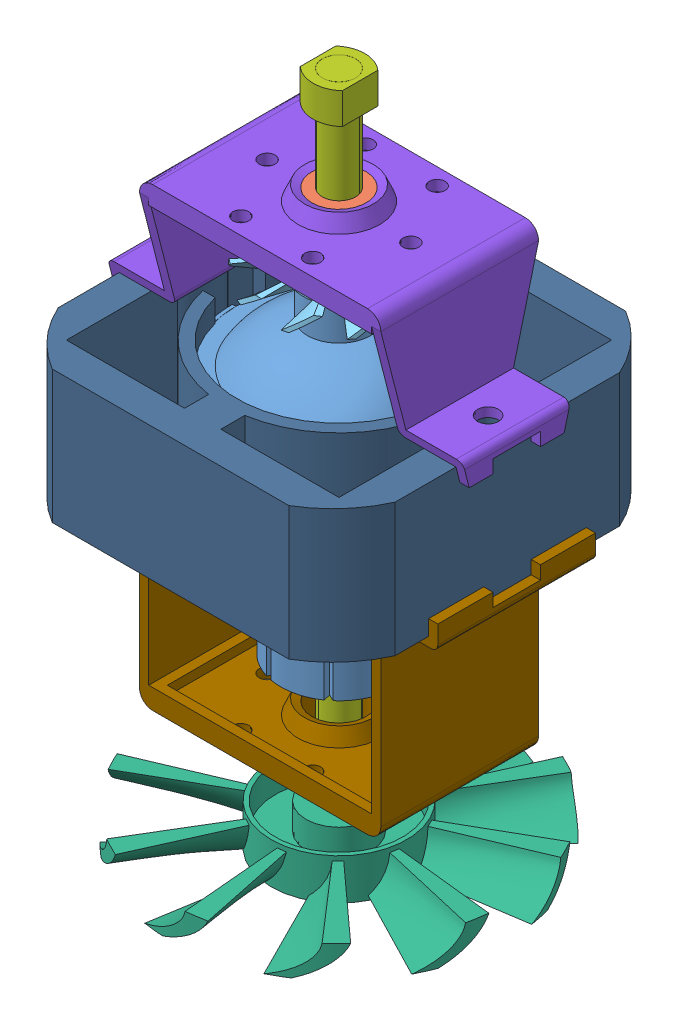
SolidWorks assembly MOTOR-SUB, configuration Default. Lengths in mm.
Overall size (67.88 128.91 64.64).
10 component instances, 10 part files, 20 mates.
Components (placement in the parent):
- motor2blender-1: motor2blender [Default] at (29.6658 20.3862 53.7649) x (-1 0 0) z (0 0 1) size (40.75 62.42 40.64)
- Motor-B-1: Motor-B [Default] at (29.6658 53.8497 53.7649) x (0.167534 0 0.985866) z (-0.985866 0 0.167534) size (10.35 7.95 10.35)
- Motor-C-1: Motor-C [Default] at (29.6658 54.0065 53.7649) x (-0.837169 0 -0.546944) z (-0.546944 0 0.837169) size (11.94 0.76 11.94)
- Motor-D-1: Motor-D [Default] at (29.6658 52.7365 53.7649) size (12.29 2.44 12.07)
- Motor-E-1: Motor-E [Default] at (29.6658 47.1358 53.7649) size (29.81 3.72 31.26)
- Motor-Fanbottom-1: Motor-Fanbottom [Default] at (29.6658 -47.4418 53.7649) size (64.26 7.82 64.64)
- Motor-shaft-1: Motor-shaft [Default] at (29.6658 -38.2978 53.7649) size (8.03 128.3 9.86)
- Motor-A-1: Motor-A [Default] at (29.6658 59.5139 53.7649) size (67.88 28.71 30.12)
- Motor-N-1: Motor-N [Default] at (29.6658 -27.4811 53.7649) x (-1 0 0) z (0 0 1) size (67.88 44.34 30.12)
- motor box pillaip-1: motor box pillaip [Default] at (29.6658 11.1269 53.7649) size (64.33 25.4 64.33)
Mates (geometry in assembly coordinates):
- Concentric1: concentric: cylinder of motor2blender-1 through (29.6658 -15.2847 53.7649) axis (0 1 0) radius 3.175; cylinder of Motor-shaft-1 through (29.6658 81.4632 53.7649) axis (0 -1 0) radius 3.175
- Concentric3: concentric: cylinder of motor2blender-1 through (29.6658 42.5765 53.7649) axis (0 1 0) radius 19.7094; cylinder of motor box pillaip-1 through (29.6658 36.5269 53.7649) axis (0 -1 0) radius 19.4564
- Coincident7: coincident: plane of Motor-A-1 through (29.6658 36.5269 97.6751) normal (0 -1 0); plane of motor box pillaip-1 through (29.6658 36.5269 53.7649) normal (0 1 0)
- Concentric8: concentric: circle of Motor-A-1; circle of motor box pillaip-1
- Concentric9: concentric: circle of Motor-A-1; circle of motor box pillaip-1
- Coincident14: coincident: plane of Motor-N-1 through (29.6658 11.1269 112.2557) normal (0 1 0); plane of motor box pillaip-1 through (29.6658 11.1269 53.7649) normal (0 -1 0)
- Concentric10: concentric: circle of Motor-N-1; circle of motor box pillaip-1
- Concentric11: concentric: circle of Motor-N-1; circle of motor box pillaip-1
- Coincident18: coincident: plane of motor2blender-1 through (29.6658 47.1358 53.7649) normal (0 1 0); plane of Motor-E-1 through (29.6658 47.1358 53.7649) normal (0 -1 0)
- Concentric12: concentric: circle of Motor-E-1; cylinder of Motor-shaft-1 through (29.6658 81.4632 53.7649) axis (0 -1 0) radius 3.175
- Coincident21: coincident: moEndPointRef_w of Motor-D-1; plane of Motor-E-1 through (29.6658 50.8442 53.7649) normal (0 1 0)
- Concentric13: concentric: circle of Motor-D-1; cylinder of Motor-shaft-1 through (29.6658 81.4632 53.7649) axis (0 -1 0) radius 3.175
- Coincident23: coincident: plane of Motor-C-1 through (29.6658 53.2445 53.7649) normal (0 -1 0); plane of Motor-D-1 through (29.6658 53.2445 53.7649) normal (0 1 0)
- Coincident24: coincident: circle of Motor-C-1; cylinder of Motor-shaft-1 through (29.6658 81.4632 53.7649) axis (0 -1 0) radius 3.175
- Coincident25: coincident: circle of Motor-B-1; cylinder of Motor-shaft-1 through (29.6658 81.4632 53.7649) axis (0 -1 0) radius 3.175
- Coincident26: coincident: circle of Motor-B-1; cylinder of Motor-A-1 through (29.6658 57.4819 53.7649) axis (0 1 0) radius 5.1753
- Concentric14: concentric: circle of Motor-B-1; cylinder of Motor-shaft-1 through (29.6658 81.4632 53.7649) axis (0 -1 0) radius 3.175
- Coincident27: coincident: plane of Motor-B-1 through (29.6658 61.7999 53.7649) normal (0 1 0); circle of Motor-A-1
- Concentric15: concentric: cylinder of Motor-Fanbottom-1 through (29.6658 -39.6186 53.7649) axis (0 -1 0) radius 2.8232; cylinder of Motor-shaft-1 through (29.6658 -45.9178 53.7649) axis (0 1 0) radius 2.8229
- Coincident28: coincident: plane of Motor-Fanbottom-1 through (29.6658 -45.9178 53.7649) normal (0 -1 0); circle of Motor-shaft-1
